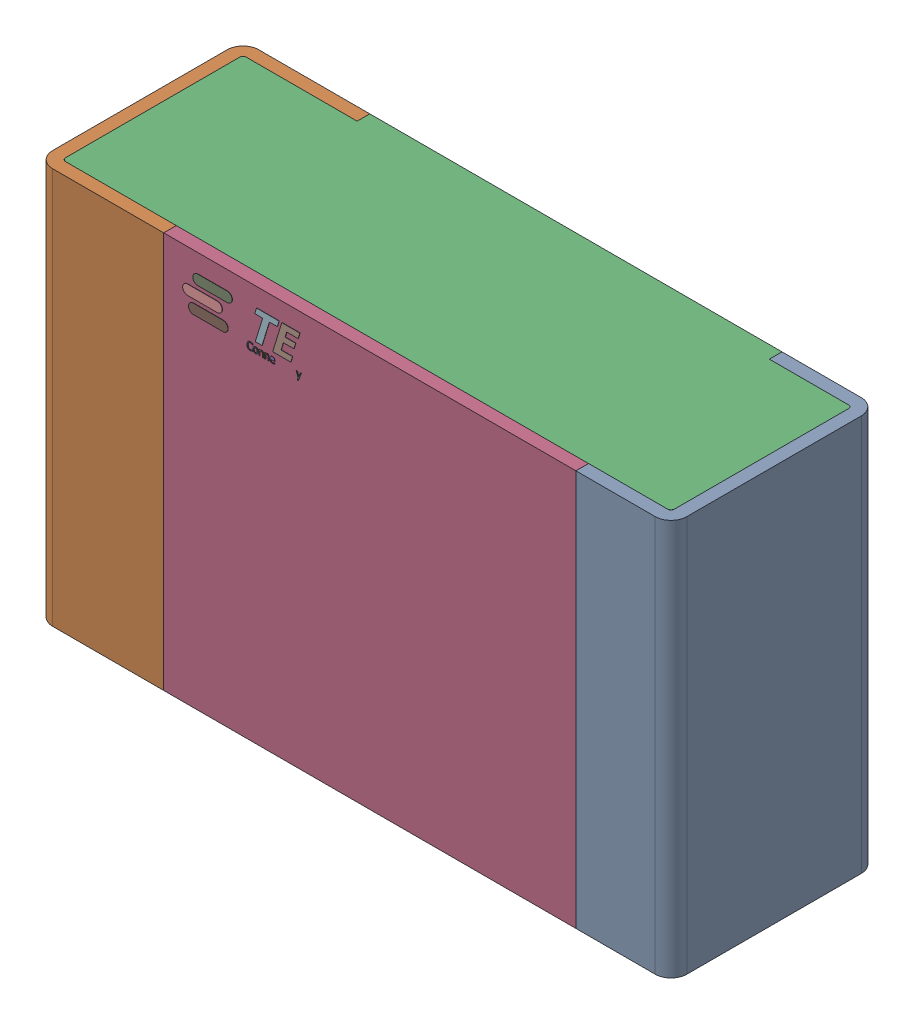
SolidWorks assembly RG.step, configuration Default. Lengths in mm.
Overall size (2 1.25 0.65).
5 component instances, 4 part files, 0 mates.
Components (placement in the parent):
- Res_TE_Connectivity_CPF0805B66R5E1_eec.step-1: Res_TE_Connectivity_CPF0805B66R5E1_eec.step [Default] at (51.153 12.827 0) size (2 1.25 0.65)
  - 1.step-1: 1.step [Default] at origin size (2 1.25 0.65)
  - 2.step-1: 2.step [Default] at origin size (1.92 1.25 0.61)
  - 3.step-1: 3.step [Default] at origin size (1.3 1.25 0.04)
  - TE connectivity Logo 1 (2).step-1: TE connectivity Logo 1 (2).step [Default] at (5.4285 0.313 0.551) x (-1 0 0) z (0 0 1) size (0.37 0.13 0.11)
